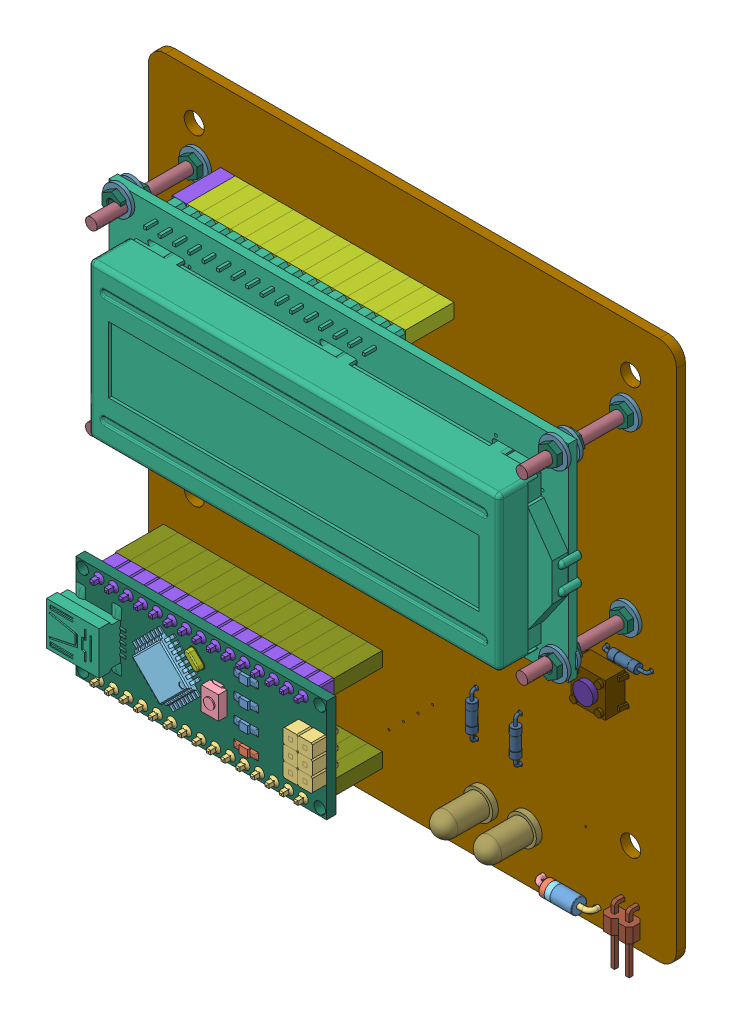
SolidWorks assembly PCB_V02, configuration Valor predeterminado. Lengths in mm.
Overall size (93.53 97.66 25.25).
163 component instances, 33 part files, 52 mates.
Components (placement in the parent):
- Gerador Senhas.stp-1: Gerador Senhas.stp [Valor predeterminado] at origin size (93.53 97.66 25.7)
  - PCB Component.stp-1: PCB Component.stp [Valor predeterminado] at origin size (93.53 97.66 25.7)
    - ARDUINO-NANO.stp-1: ARDUINO-NANO.stp [Valor predeterminado] at (39.37 21.59 1.57) x (0 -1 0) z (0 0 1) size (17.9 45.1 23.75)
      - PCB.stp-1: PCB.stp [Valor predeterminado] at (-1.2568 4.2028 12.5) x (0 -1 0) z (1 0 0) size (45.1 18 17.9)
        - TopFace.stp-1: TopFace.stp [Valor predeterminado] at origin size (45.1 11.25 12.1)
          - Leds.stp-1: Leds.stp [Valor predeterminado] at origin size (4.2 0.5 12.1)
            - Led.stp-1: Led.stp [Valor predeterminado] at (3.25 0 -13.6) size (4.2 0.5 1.3)
            - Led.stp-2: Led.stp [Valor predeterminado] at (3.25 0 -17.2) size (4.2 0.5 1.3)
            - Led.stp-3: Led.stp [Valor predeterminado] at (3.25 0 -20.8) size (4.2 0.5 1.3)
            - Led (1).stp-1: Led (1).stp [Valor predeterminado] at (3.25 0 -10) size (4.2 0.5 1.3)
          - PinEnd.stp-1: PinEnd.stp [Valor predeterminado] at (0 0 -2.54) size (5.08 11.25 7.62)
            - Pin.stp-1: Pin.stp [Valor predeterminado] at (25 1.6 57.68) x (1 0 0) z (0 0 -1) size (2.54 11.25 2.54)
            - Pin.stp-2: Pin.stp [Valor predeterminado] at (25 1.6 60.22) x (1 0 0) z (0 0 -1) size (2.54 11.25 2.54)
            - Pin.stp-3: Pin.stp [Valor predeterminado] at (25 1.6 62.76) x (1 0 0) z (0 0 -1) size (2.54 11.25 2.54)
            - Pin.stp-4: Pin.stp [Valor predeterminado] at (27.54 1.6 57.68) x (1 0 0) z (0 0 -1) size (2.54 11.25 2.54)
            - Pin.stp-5: Pin.stp [Valor predeterminado] at (27.54 1.6 60.22) x (1 0 0) z (0 0 -1) size (2.54 11.25 2.54)
            - Pin.stp-6: Pin.stp [Valor predeterminado] at (27.54 1.6 62.76) x (1 0 0) z (0 0 -1) size (2.54 11.25 2.54)
          - switch.stp-1: switch.stp [Valor predeterminado] at (1.3966 -1.5 22.3391) size (3 1.7 4.8)
          - chip1.stp-1: chip1.stp [Valor predeterminado] at origin size (11.76 1.3 11.76)
          - USB.stp-1: USB.stp [Valor predeterminado] at origin size (10.18 3.8 11.01)
          - Crystal.stp-1: Crystal.stp [Valor predeterminado] at origin size (2.71 1.1 2.71)
        - BottomFace.stp-1: BottomFace.stp [Valor predeterminado] at origin size (40.75 11.25 17.9)
          - PinRow2.stp-1: PinRow2.stp [Valor predeterminado] at (0 0 17.9) size (38.1 11.25 2.54)
            - Pin (1).stp-1: Pin (1).stp [Valor predeterminado] at (45.58 0 32.1) size (2.54 11.25 2.54)
            - Pin (1).stp-2: Pin (1).stp [Valor predeterminado] at (48.12 0 32.1) size (2.54 11.25 2.54)
            - Pin (1).stp-3: Pin (1).stp [Valor predeterminado] at (50.66 0 32.1) size (2.54 11.25 2.54)
            - Pin (1).stp-4: Pin (1).stp [Valor predeterminado] at (53.2 0 32.1) size (2.54 11.25 2.54)
            - Pin (1).stp-5: Pin (1).stp [Valor predeterminado] at (55.74 0 32.1) size (2.54 11.25 2.54)
            - Pin (1).stp-6: Pin (1).stp [Valor predeterminado] at (58.28 0 32.1) size (2.54 11.25 2.54)
            - Pin (1).stp-7: Pin (1).stp [Valor predeterminado] at (60.82 0 32.1) size (2.54 11.25 2.54)
            - Pin (1).stp-8: Pin (1).stp [Valor predeterminado] at (63.36 0 32.1) size (2.54 11.25 2.54)
            - Pin (1).stp-9: Pin (1).stp [Valor predeterminado] at (43.04 0 32.1) size (2.54 11.25 2.54)
            - Pin (1).stp-10: Pin (1).stp [Valor predeterminado] at (40.5 0 32.1) size (2.54 11.25 2.54)
            - Pin (1).stp-11: Pin (1).stp [Valor predeterminado] at (37.96 0 32.1) size (2.54 11.25 2.54)
            - Pin (1).stp-12: Pin (1).stp [Valor predeterminado] at (35.42 0 32.1) size (2.54 11.25 2.54)
            - Pin (1).stp-13: Pin (1).stp [Valor predeterminado] at (32.88 0 32.1) size (2.54 11.25 2.54)
            - Pin (1).stp-14: Pin (1).stp [Valor predeterminado] at (30.34 0 32.1) size (2.54 11.25 2.54)
            - Pin (1).stp-15: Pin (1).stp [Valor predeterminado] at (27.8 0 32.1) size (2.54 11.25 2.54)
          - PinRow1.stp-1: PinRow1.stp [Valor predeterminado] at origin size (38.1 11.25 2.54)
            - Pin.stp-1: Pin.stp [Valor predeterminado] at (45.58 0 -32.1) size (2.54 11.25 2.54)
            - Pin.stp-2: Pin.stp [Valor predeterminado] at (48.12 0 -32.1) size (2.54 11.25 2.54)
            - Pin.stp-3: Pin.stp [Valor predeterminado] at (50.66 0 -32.1) size (2.54 11.25 2.54)
            - Pin.stp-4: Pin.stp [Valor predeterminado] at (53.2 0 -32.1) size (2.54 11.25 2.54)
            - Pin.stp-5: Pin.stp [Valor predeterminado] at (55.74 0 -32.1) size (2.54 11.25 2.54)
            - Pin.stp-6: Pin.stp [Valor predeterminado] at (58.28 0 -32.1) size (2.54 11.25 2.54)
            - Pin.stp-7: Pin.stp [Valor predeterminado] at (60.82 0 -32.1) size (2.54 11.25 2.54)
            - Pin.stp-8: Pin.stp [Valor predeterminado] at (63.36 0 -32.1) size (2.54 11.25 2.54)
            - Pin.stp-9: Pin.stp [Valor predeterminado] at (43.04 0 -32.1) size (2.54 11.25 2.54)
            - Pin.stp-10: Pin.stp [Valor predeterminado] at (40.5 0 -32.1) size (2.54 11.25 2.54)
            - Pin.stp-11: Pin.stp [Valor predeterminado] at (37.96 0 -32.1) size (2.54 11.25 2.54)
            - Pin.stp-12: Pin.stp [Valor predeterminado] at (35.42 0 -32.1) size (2.54 11.25 2.54)
            - Pin.stp-13: Pin.stp [Valor predeterminado] at (32.88 0 -32.1) size (2.54 11.25 2.54)
            - Pin.stp-14: Pin.stp [Valor predeterminado] at (30.34 0 -32.1) size (2.54 11.25 2.54)
            - Pin.stp-15: Pin.stp [Valor predeterminado] at (27.8 0 -32.1) size (2.54 11.25 2.54)
          - Resistors.stp-1: Resistors.stp [Valor predeterminado] at origin size (32.5 1 11.3)
            - Res.stp-1: Res.stp [Valor predeterminado] at (12.2 1.6 29.15) x (0 0 -1) z (1 0 0) size (1.3 1 4)
            - Res.stp-2: Res.stp [Valor predeterminado] at (12.2 1.6 24.6) x (0 0 -1) z (1 0 0) size (1.3 1 4)
            - Res.stp-3: Res.stp [Valor predeterminado] at (-2.9 1.6 23.1) x (0 0 -1) z (1 0 0) size (1.3 1 4)
            - Res.stp-4: Res.stp [Valor predeterminado] at (-2.9 1.6 26.2) x (0 0 -1) z (1 0 0) size (1.3 1 4)
            - Res.stp-5: Res.stp [Valor predeterminado] at (-16.3 1.6 19.15) x (0 0 -1) z (1 0 0) size (1.3 1 4)
          - caps.stp-1: caps.stp [Valor predeterminado] at origin size (33.2 1.51 4.35)
            - cap.stp-1: cap.stp [Valor predeterminado] at (68.25 1.6 43.825) x (-1 0 0) z (0 0 -1) size (3.7 1.51 1.65)
            - cap.stp-2: cap.stp [Valor predeterminado] at (-14.35 1.6 -32.125) size (3.7 1.51 1.65)
          - respacks.stp-1: respacks.stp [Valor predeterminado] at origin size (3.22 0.9 8.4)
            - respack.stp-1: respack.stp [Valor predeterminado] at (-0.85 1.6 -21.8) size (3.22 0.9 3.4)
            - respack.stp-2: respack.stp [Valor predeterminado] at (-0.85 1.6 -26.8) size (3.22 0.9 3.4)
          - Chip.stp-1: Chip.stp [Valor predeterminado] at origin size (10 1.5 8.03)
          - diode.stp-1: diode.stp [Valor predeterminado] at (0.15 1.6 -28.35) size (1.6 1 4.3)
          - vreg.stp-1: vreg.stp [Valor predeterminado] at (-16.3 1.6 -15.5) size (8.5 1.6 6)
        - PCB-0.stp-1: PCB-0.stp [Valor predeterminado] at origin size (43.7 1.6 17.9)
      - Headers.stp-1: Headers.stp [Valor predeterminado] at (-1.2568 4.2028 12.5) x (0 -1 0) z (1 0 0) size (38.1 11.45 17.78)
        - Header Female 15 v1.stp-1: Header Female 15 v1.stp [Valor predeterminado] at (4.07 12.55 16.51) x (1 0 0) z (0 -1 0) size (38.1 2.54 11.45)
          - HF1.stp-1: HF1.stp [Valor predeterminado] at origin size (2.54 2.54 11.45)
          - HF1.stp-2: HF1.stp [Valor predeterminado] at (2.54 0 0) size (2.54 2.54 11.45)
          - HF1.stp-3: HF1.stp [Valor predeterminado] at (5.08 0 0) size (2.54 2.54 11.45)
          - HF1.stp-4: HF1.stp [Valor predeterminado] at (7.62 0 0) size (2.54 2.54 11.45)
          - HF1.stp-5: HF1.stp [Valor predeterminado] at (10.16 0 0) size (2.54 2.54 11.45)
          - HF1.stp-6: HF1.stp [Valor predeterminado] at (12.7 0 0) size (2.54 2.54 11.45)
          - HF1.stp-7: HF1.stp [Valor predeterminado] at (15.24 0 0) size (2.54 2.54 11.45)
          - HF1.stp-8: HF1.stp [Valor predeterminado] at (17.78 0 0) size (2.54 2.54 11.45)
          - HF1.stp-9: HF1.stp [Valor predeterminado] at (20.32 0 0) size (2.54 2.54 11.45)
          - HF1.stp-10: HF1.stp [Valor predeterminado] at (22.86 0 0) size (2.54 2.54 11.45)
          - HF1.stp-11: HF1.stp [Valor predeterminado] at (25.4 0 0) size (2.54 2.54 11.45)
          - HF1.stp-12: HF1.stp [Valor predeterminado] at (27.94 0 0) size (2.54 2.54 11.45)
          - HF1.stp-13: HF1.stp [Valor predeterminado] at (30.48 0 0) size (2.54 2.54 11.45)
          - HF1.stp-14: HF1.stp [Valor predeterminado] at (33.02 0 0) size (2.54 2.54 11.45)
          - HF1.stp-15: HF1.stp [Valor predeterminado] at (35.56 0 0) size (2.54 2.54 11.45)
        - Header Female 15 v1 (1).stp-1: Header Female 15 v1 (1).stp [Valor predeterminado] at (4.07 12.55 1.27) x (1 0 0) z (0 -1 0) size (38.1 2.54 11.45)
          - HF1.stp-1: HF1.stp [Valor predeterminado] at origin size (2.54 2.54 11.45)
          - HF1.stp-2: HF1.stp [Valor predeterminado] at (2.54 0 0) size (2.54 2.54 11.45)
          - HF1.stp-3: HF1.stp [Valor predeterminado] at (5.08 0 0) size (2.54 2.54 11.45)
          - HF1.stp-4: HF1.stp [Valor predeterminado] at (7.62 0 0) size (2.54 2.54 11.45)
          - HF1.stp-5: HF1.stp [Valor predeterminado] at (10.16 0 0) size (2.54 2.54 11.45)
          - HF1.stp-6: HF1.stp [Valor predeterminado] at (12.7 0 0) size (2.54 2.54 11.45)
          - HF1.stp-7: HF1.stp [Valor predeterminado] at (15.24 0 0) size (2.54 2.54 11.45)
          - HF1.stp-8: HF1.stp [Valor predeterminado] at (17.78 0 0) size (2.54 2.54 11.45)
          - HF1.stp-9: HF1.stp [Valor predeterminado] at (20.32 0 0) size (2.54 2.54 11.45)
          - HF1.stp-10: HF1.stp [Valor predeterminado] at (22.86 0 0) size (2.54 2.54 11.45)
          - HF1.stp-11: HF1.stp [Valor predeterminado] at (25.4 0 0) size (2.54 2.54 11.45)
          - HF1.stp-12: HF1.stp [Valor predeterminado] at (27.94 0 0) size (2.54 2.54 11.45)
          - HF1.stp-13: HF1.stp [Valor predeterminado] at (30.48 0 0) size (2.54 2.54 11.45)
          - HF1.stp-14: HF1.stp [Valor predeterminado] at (33.02 0 0) size (2.54 2.54 11.45)
          - HF1.stp-15: HF1.stp [Valor predeterminado] at (35.56 0 0) size (2.54 2.54 11.45)
    - PUSHBUTTON.stp-1: PUSHBUTTON.stp [Valor predeterminado] at (12 38.1 1.57) size (7.7 6 7.8)
      - B3F_1000_BUTTON.stp-1: B3F_1000_BUTTON.stp [Valor predeterminado] at (0 0 4.3) x (-1 0 0) z (0 1 0) size (3.5 1 3.5)
      - B3F_1000_BASE.stp-1: B3F_1000_BASE.stp [Valor predeterminado] x (1 0 0) z (0 -1 0) size (7.7 7.4 6)
    - PUSHBUTTON.stp-2: PUSHBUTTON.stp [Valor predeterminado] at (34.667 38.1 1.57) size (7.7 6 7.8)
      - B3F_1000_BUTTON.stp-1: B3F_1000_BUTTON.stp [Valor predeterminado] at (0 0 4.3) x (-1 0 0) z (0 1 0) size (3.5 1 3.5)
      - B3F_1000_BASE.stp-1: B3F_1000_BASE.stp [Valor predeterminado] x (1 0 0) z (0 -1 0) size (7.7 7.4 6)
    - PUSHBUTTON.stp-3: PUSHBUTTON.stp [Valor predeterminado] at (57.333 38.1 1.57) size (7.7 6 7.8)
      - B3F_1000_BUTTON.stp-1: B3F_1000_BUTTON.stp [Valor predeterminado] at (0 0 4.3) x (-1 0 0) z (0 1 0) size (3.5 1 3.5)
      - B3F_1000_BASE.stp-1: B3F_1000_BASE.stp [Valor predeterminado] x (1 0 0) z (0 -1 0) size (7.7 7.4 6)
    - PUSHBUTTON.stp-4: PUSHBUTTON.stp [Valor predeterminado] at (80 38.1 1.57) size (7.7 6 7.8)
      - B3F_1000_BUTTON.stp-1: B3F_1000_BUTTON.stp [Valor predeterminado] at (0 0 4.3) x (-1 0 0) z (0 1 0) size (3.5 1 3.5)
      - B3F_1000_BASE.stp-1: B3F_1000_BASE.stp [Valor predeterminado] x (1 0 0) z (0 -1 0) size (7.7 7.4 6)
    - 1N4004.stp-1: 1N4004.stp [Valor predeterminado] at (73.66 2.54 1.57) size (10.38 2.7 5.35)
      - User Library-DO-41_375mil_Fillet001.stp-1: User Library-DO-41_375mil_Fillet001.stp [Valor predeterminado] at (4.7457 0.3612 0) x (-1 0 0) z (0 0 1) size (3.72 2.7 2.7)
      - User Library-DO-41_375mil_Fillet.stp-1: User Library-DO-41_375mil_Fillet.stp [Valor predeterminado] at (4.7457 0.3612 0) x (-1 0 0) z (0 0 1) size (1 2.7 2.7)
      - User Library-DO-41_375mil_DO_41_375mil001.stp-1: User Library-DO-41_375mil_DO_41_375mil001.stp [Valor predeterminado] at (4.7457 0.3612 0) x (-1 0 0) z (0 0 1) size (2.55 0.86 4.43)
      - User Library-DO-41_375mil_DO_41_375mil.stp-1: User Library-DO-41_375mil_DO_41_375mil.stp [Valor predeterminado] at (4.7457 0.3612 0) x (-1 0 0) z (0 0 1) size (2.55 0.86 4.43)
      - User Library-DO-41_375mil_DO_41_375mil003.stp-1: User Library-DO-41_375mil_DO_41_375mil003.stp [Valor predeterminado] at (4.7457 0.3612 0) x (-1 0 0) z (0 0 1) size (1 2.7 2.7)
    - LCD-16X2-V2.stp-1: LCD-16X2-V2.stp [Valor predeterminado] at (46 64.77 1.57) size (80.7 36 23.25)
      - DISPLAY-LCD.stp-1: DISPLAY-LCD.stp [Valor predeterminado] at (-0.3985 0.0488 8.5541) size (80.7 36 16.8)
      - Header Female 15 v1 (2).stp-1: Header Female 15 v1 (2).stp [Valor predeterminado] at (-29.5885 15.5718 0.0005) size (38.1 2.54 11.45)
      - Header Female 15 v1 - Copia.stp-1: Header Female 15 v1 - Copia.stp [Valor predeterminado] at (-32.1285 15.5718 0.0005) size (2.54 2.54 11.45)
    - Board.stp-1: Board.stp [Valor predeterminado] at origin size (92 94 1.57)
    - 10k.stp-1: 10k.stp [Valor predeterminado] at (57.15 21.59 1.57) x (0 1 0) z (0 0 1) size (8.2 1.6 3.52)
    - 10k.stp-2: 10k.stp [Valor predeterminado] at (64.77 21.59 1.57) x (0 1 0) z (0 0 1) size (8.2 1.6 3.52)
    - 10k.stp-3: 10k.stp [Valor predeterminado] at (15.24 43.18 1.57) size (8.2 1.6 3.52)
    - 10k.stp-4: 10k.stp [Valor predeterminado] at (38.1 43.18 1.57) size (8.2 1.6 3.52)
    - 10k.stp-5: 10k.stp [Valor predeterminado] at (60.96 43.18 1.57) size (8.2 1.6 3.52)
    - 10k.stp-6: 10k.stp [Valor predeterminado] at (83.82 43.18 1.57) size (8.2 1.6 3.52)
    - 1X02_90.stp-1: 1X02_90.stp [Valor predeterminado] at (83.82 2.54 1.57) x (-1 0 0) z (0 0 1) size (5.08 10.36 5.54)
    - LED5MM.stp-1: LED5MM.stp [Valor predeterminado] at (58.42 8.89 1.57) size (5.1 5.1 13.6)
    - LED5MM.stp-2: LED5MM.stp [Valor predeterminado] at (66.04 8.89 1.57) size (5.1 5.1 13.6)
- pan head cross recess screw_iso-1: pan head cross recess screw_iso [ISO 7045 - M2 x 20 - Z - 20N] at (83.5 80.27 -1.6) x (0 0 1) z (-1 0 0) size (21.57 4 4)
- pan head cross recess screw_iso-2: pan head cross recess screw_iso [ISO 7045 - M2 x 20 - Z - 20N] at (83.5 49.27 -1.6) x (0 0 1) z (-1 0 0) size (21.57 4 4)
- pan head cross recess screw_iso-3: pan head cross recess screw_iso [ISO 7045 - M2 x 20 - Z - 20N] at (8.5 49.27 -1.6) x (0 0 1) z (-1 0 0) size (21.57 4 4)
- pan head cross recess screw_iso-4: pan head cross recess screw_iso [ISO 7045 - M2 x 20 - Z - 20N] at (8.5 80.27 -1.6) x (0 0 1) z (-1 0 0) size (21.57 4 4)
- plain washer 10673 type snl_iso-1: plain washer 10673 type snl_iso [ISO 10673-2.25-S] at (83.5 80.27 1.57) x (0 0 1) z (-1 0 0) size (0.6 5 5)
- plain washer 10673 type snl_iso-2: plain washer 10673 type snl_iso [ISO 10673-2.25-S] at (83.6015 80.6118 14.0205) x (0 0 1) z (-1 0 0) size (0.6 5 5)
- plain washer 10673 type snl_iso-3: plain washer 10673 type snl_iso [ISO 10673-2.25-S] at (83.6015 80.6118 12.5205) x (0 0 -1) z (1 0 0) size (0.6 5 5)
- plain washer 10673 type snl_iso-4: plain washer 10673 type snl_iso [ISO 10673-2.25-S] at (83.5 49.27 12.2061) x (0 0 1) z (-1 0 0) size (0.6 5 5)
- plain washer 10673 type snl_iso-5: plain washer 10673 type snl_iso [ISO 10673-2.25-S] at (83.6015 48.6118 14.0205) x (0 0 1) z (-1 0 0) size (0.6 5 5)
- plain washer 10673 type snl_iso-6: plain washer 10673 type snl_iso [ISO 10673-2.25-S] at (83.5 49.27 1.57) x (0 0 1) z (-1 0 0) size (0.6 5 5)
- plain washer 10673 type snl_iso-7: plain washer 10673 type snl_iso [ISO 10673-2.25-S] at (8.5 49.27 1.763) x (0 0 1) z (-1 0 0) size (0.6 5 5)
- plain washer 10673 type snl_iso-8: plain washer 10673 type snl_iso [ISO 10673-2.25-S] at (7.6015 48.6118 14.0205) x (0 0 1) z (-1 0 0) size (0.6 5 5)
- plain washer 10673 type snl_iso-9: plain washer 10673 type snl_iso [ISO 10673-2.25-S] at (7.6015 80.6118 14.0205) x (0 0 1) z (-1 0 0) size (0.6 5 5)
- plain washer 10673 type snl_iso-10: plain washer 10673 type snl_iso [ISO 10673-2.25-S] at (8.5 80.27 1.57) x (0 0 1) z (-1 0 0) size (0.6 5 5)
- plain washer 10673 type snl_iso-12: plain washer 10673 type snl_iso [ISO 10673-2.25-S] at (7.6015 48.6118 12.5205) x (0 0 -1) z (1 0 0) size (0.6 5 5)
- plain washer 10673 type snl_iso-13: plain washer 10673 type snl_iso [ISO 10673-2.25-S] at (7.6015 80.6118 12.5205) x (0 0 -1) z (1 0 0) size (0.6 5 5)
- hex thin nut gradeb_iso-2: hex thin nut gradeb_iso [ISO - 4036 - M1.6 - N] at (83.6015 80.6118 15.6205) size (3.2 3.7 1)
- hex thin nut gradeb_iso-3: hex thin nut gradeb_iso [ISO - 4036 - M1.6 - N] at (83.5 80.27 3.17) size (3.2 3.7 1)
- hex thin nut gradeb_iso-4: hex thin nut gradeb_iso [ISO - 4036 - M1.6 - N] at (83.6015 80.6118 10.9205) x (0.923728 0.383049 0) z (0 0 -1) size (3.2 3.7 1)
- hex thin nut gradeb_iso-5: hex thin nut gradeb_iso [ISO - 4036 - M1.6 - N] at (83.5 49.27 11.2061) x (0.923728 0.383049 0) z (0 0 -1) size (3.2 3.7 1)
- hex thin nut gradeb_iso-6: hex thin nut gradeb_iso [ISO - 4036 - M1.6 - N] at (83.5 49.27 3.17) size (3.2 3.7 1)
- hex thin nut gradeb_iso-7: hex thin nut gradeb_iso [ISO - 4036 - M1.6 - N] at (83.6015 48.6118 15.6205) size (3.2 3.7 1)
- hex thin nut gradeb_iso-8: hex thin nut gradeb_iso [ISO - 4036 - M1.6 - N] at (7.6015 80.6118 15.6205) size (3.2 3.7 1)
- hex thin nut gradeb_iso-9: hex thin nut gradeb_iso [ISO - 4036 - M1.6 - N] at (7.6015 48.6118 15.6205) size (3.2 3.7 1)
- hex thin nut gradeb_iso-10: hex thin nut gradeb_iso [ISO - 4036 - M1.6 - N] at (7.6015 48.6118 10.9205) x (0.923728 0.383049 0) z (0 0 -1) size (3.2 3.7 1)
- hex thin nut gradeb_iso-11: hex thin nut gradeb_iso [ISO - 4036 - M1.6 - N] at (8.5 80.27 10.9205) x (-0.825808 -0.563951 0) z (0 0 -1) size (3.2 3.7 1)
- hex thin nut gradeb_iso-12: hex thin nut gradeb_iso [ISO - 4036 - M1.6 - N] at (8.5 80.27 3.17) size (3.2 3.7 1)
- hex thin nut gradeb_iso-13: hex thin nut gradeb_iso [ISO - 4036 - M1.6 - N] at (8.5 49.27 3.363) size (3.2 3.7 1)
Mates (geometry in assembly coordinates):
- Concêntrico1: concentric anti-aligned: cylinder of Gerador Senhas.stp-1/PCB Component.stp-1/Board.stp-1 through (83.5 80.27 0) axis (0 0 1) radius 1.25; cylinder of pan head cross recess screw_iso-1 through (83.5 80.27 -27) axis (0 0 -1) radius 2
- Coincidente1: coincident anti-aligned: plane of Gerador Senhas.stp-1/PCB Component.stp-1/Board.stp-1 through (46 47 0) normal (0 0 -1); plane of pan head cross recess screw_iso-1 through (83.5 81.27 0) normal (0 0 1)
- Concêntrico2: concentric anti-aligned: cylinder of Gerador Senhas.stp-1/PCB Component.stp-1/Board.stp-1 through (83.5 49.27 0) axis (0 0 1) radius 1.25; cylinder of pan head cross recess screw_iso-2 through (83.5 49.27 -27) axis (0 0 -1) radius 2
- Coincidente2: coincident anti-aligned: plane of Gerador Senhas.stp-1/PCB Component.stp-1/Board.stp-1 through (46 47 0) normal (0 0 -1); plane of pan head cross recess screw_iso-2 through (83.5 50.27 0) normal (0 0 1)
- Concêntrico3: concentric anti-aligned: cylinder of Gerador Senhas.stp-1/PCB Component.stp-1/Board.stp-1 through (8.5 49.27 0) axis (0 0 1) radius 1.25; cylinder of pan head cross recess screw_iso-3 through (8.5 49.27 -27) axis (0 0 -1) radius 2
- Coincidente3: coincident anti-aligned: plane of Gerador Senhas.stp-1/PCB Component.stp-1/Board.stp-1 through (46 47 0) normal (0 0 -1); plane of pan head cross recess screw_iso-3 through (8.5 50.27 0) normal (0 0 1)
- Concêntrico4: concentric anti-aligned: cylinder of Gerador Senhas.stp-1/PCB Component.stp-1/Board.stp-1 through (8.5 80.27 0) axis (0 0 1) radius 1.25; cylinder of pan head cross recess screw_iso-4 through (8.5 80.27 -27) axis (0 0 -1) radius 2
- Coincidente4: coincident anti-aligned: plane of Gerador Senhas.stp-1/PCB Component.stp-1/Board.stp-1 through (46 47 0) normal (0 0 -1); plane of pan head cross recess screw_iso-4 through (8.5 81.27 0) normal (0 0 1)
- Concêntrico6: concentric anti-aligned: cylinder of Gerador Senhas.stp-1/PCB Component.stp-1/Board.stp-1 through (83.5 80.27 0) axis (0 0 1) radius 1.25; cylinder of plain washer 10673 type snl_iso-1 through (83.5 80.27 2.17) axis (0 0 -1) radius 1.125
- Coincidente5: coincident anti-aligned: plane of Gerador Senhas.stp-1/PCB Component.stp-1/Board.stp-1 through (46 47 1.57) normal (0 0 1); plane of plain washer 10673 type snl_iso-1 through (83.5 80.27 1.57) normal (0 0 -1)
- Concêntrico7: concentric aligned: cylinder of Gerador Senhas.stp-1/PCB Component.stp-1/LCD-16X2-V2.stp-1/DISPLAY-LCD.stp-1 through (83.6015 80.6118 12.5205) axis (0 0 -1) radius 1.5; cylinder of plain washer 10673 type snl_iso-2 through (83.6015 80.6118 14.6205) axis (0 0 -1) radius 1.125
- Coincidente6: coincident anti-aligned: plane of Gerador Senhas.stp-1/PCB Component.stp-1/LCD-16X2-V2.stp-1/DISPLAY-LCD.stp-1 through (45.6015 64.6118 14.0205) normal (0 0 1); plane of plain washer 10673 type snl_iso-2 through (83.6015 80.6118 14.0205) normal (0 0 -1)
- Concêntrico8: concentric anti-aligned: cylinder of Gerador Senhas.stp-1/PCB Component.stp-1/LCD-16X2-V2.stp-1/DISPLAY-LCD.stp-1 through (83.6015 80.6118 12.5205) axis (0 0 -1) radius 1.5; cylinder of plain washer 10673 type snl_iso-3 through (83.6015 80.6118 11.9205) axis (0 0 1) radius 1.125
- Coincidente7: coincident anti-aligned: plane of Gerador Senhas.stp-1/PCB Component.stp-1/LCD-16X2-V2.stp-1/DISPLAY-LCD.stp-1 through (45.6015 64.6118 12.5205) normal (0 0 -1); plane of plain washer 10673 type snl_iso-3 through (83.6015 80.6118 12.5205) normal (0 0 1)
- Concêntrico9: concentric aligned: cylinder of pan head cross recess screw_iso-2 through (83.5 49.27 -27) axis (0 0 -1) radius 1; cylinder of plain washer 10673 type snl_iso-4 through (83.5 49.27 12.8061) axis (0 0 -1) radius 1.125
- Concêntrico10: concentric aligned: cylinder of Gerador Senhas.stp-1/PCB Component.stp-1/LCD-16X2-V2.stp-1/DISPLAY-LCD.stp-1 through (83.6015 48.6118 12.5205) axis (0 0 -1) radius 1.5; cylinder of plain washer 10673 type snl_iso-5 through (83.6015 48.6118 14.6205) axis (0 0 -1) radius 1.125
- Coincidente8: coincident anti-aligned: plane of Gerador Senhas.stp-1/PCB Component.stp-1/LCD-16X2-V2.stp-1/DISPLAY-LCD.stp-1 through (45.6015 64.6118 14.0205) normal (0 0 1); plane of plain washer 10673 type snl_iso-5 through (83.6015 48.6118 14.0205) normal (0 0 -1)
- Concêntrico11: concentric anti-aligned: cylinder of Gerador Senhas.stp-1/PCB Component.stp-1/Board.stp-1 through (83.5 49.27 0) axis (0 0 1) radius 1.25; cylinder of plain washer 10673 type snl_iso-6 through (83.5 49.27 2.17) axis (0 0 -1) radius 1.125
- Coincidente9: coincident anti-aligned: plane of Gerador Senhas.stp-1/PCB Component.stp-1/Board.stp-1 through (46 47 1.57) normal (0 0 1); plane of plain washer 10673 type snl_iso-6 through (83.5 49.27 1.57) normal (0 0 -1)
- Concêntrico12: concentric aligned: cylinder of pan head cross recess screw_iso-3 through (8.5 49.27 -27) axis (0 0 -1) radius 1; cylinder of plain washer 10673 type snl_iso-7 through (8.5 49.27 2.363) axis (0 0 -1) radius 1.125
- Concêntrico13: concentric aligned: cylinder of Gerador Senhas.stp-1/PCB Component.stp-1/LCD-16X2-V2.stp-1/DISPLAY-LCD.stp-1 through (7.6015 48.6118 12.5205) axis (0 0 -1) radius 1.5; cylinder of plain washer 10673 type snl_iso-8 through (7.6015 48.6118 14.6205) axis (0 0 -1) radius 1.125
- Coincidente10: coincident anti-aligned: plane of Gerador Senhas.stp-1/PCB Component.stp-1/LCD-16X2-V2.stp-1/DISPLAY-LCD.stp-1 through (45.6015 64.6118 14.0205) normal (0 0 1); plane of plain washer 10673 type snl_iso-8 through (7.6015 48.6118 14.0205) normal (0 0 -1)
- Concêntrico14: concentric aligned: cylinder of Gerador Senhas.stp-1/PCB Component.stp-1/LCD-16X2-V2.stp-1/DISPLAY-LCD.stp-1 through (7.6015 80.6118 12.5205) axis (0 0 -1) radius 1.5; cylinder of plain washer 10673 type snl_iso-9 through (7.6015 80.6118 14.6205) axis (0 0 -1) radius 1.125
- Coincidente11: coincident anti-aligned: plane of Gerador Senhas.stp-1/PCB Component.stp-1/LCD-16X2-V2.stp-1/DISPLAY-LCD.stp-1 through (45.6015 64.6118 14.0205) normal (0 0 1); plane of plain washer 10673 type snl_iso-9 through (7.6015 80.6118 14.0205) normal (0 0 -1)
- Concêntrico15: concentric anti-aligned: cylinder of Gerador Senhas.stp-1/PCB Component.stp-1/Board.stp-1 through (8.5 80.27 0) axis (0 0 1) radius 1.25; cylinder of plain washer 10673 type snl_iso-10 through (8.5 80.27 2.17) axis (0 0 -1) radius 1.125
- Coincidente12: coincident anti-aligned: plane of Gerador Senhas.stp-1/PCB Component.stp-1/Board.stp-1 through (46 47 1.57) normal (0 0 1); plane of plain washer 10673 type snl_iso-10 through (8.5 80.27 1.57) normal (0 0 -1)
- Concêntrico17: concentric anti-aligned: cylinder of Gerador Senhas.stp-1/PCB Component.stp-1/LCD-16X2-V2.stp-1/DISPLAY-LCD.stp-1 through (7.6015 48.6118 12.5205) axis (0 0 -1) radius 1.5; cylinder of plain washer 10673 type snl_iso-12 through (7.6015 48.6118 11.9205) axis (0 0 1) radius 1.125
- Coincidente13: coincident anti-aligned: plane of Gerador Senhas.stp-1/PCB Component.stp-1/LCD-16X2-V2.stp-1/DISPLAY-LCD.stp-1 through (45.6015 64.6118 12.5205) normal (0 0 -1); plane of plain washer 10673 type snl_iso-12 through (7.6015 48.6118 12.5205) normal (0 0 1)
- Concêntrico181: concentric anti-aligned: cylinder of Gerador Senhas.stp-1/PCB Component.stp-1/LCD-16X2-V2.stp-1/DISPLAY-LCD.stp-1 through (7.6015 80.6118 12.5205) axis (0 0 -1) radius 1.5; cylinder of plain washer 10673 type snl_iso-13 through (7.6015 80.6118 11.9205) axis (0 0 1) radius 1.125
- Coincidente141: coincident anti-aligned: plane of Gerador Senhas.stp-1/PCB Component.stp-1/LCD-16X2-V2.stp-1/DISPLAY-LCD.stp-1 through (45.6015 64.6118 12.5205) normal (0 0 -1); plane of plain washer 10673 type snl_iso-13 through (7.6015 80.6118 12.5205) normal (0 0 1)
- Concêntrico20: concentric anti-aligned: cylinder of plain washer 10673 type snl_iso-2 through (83.6015 80.6118 14.6205) axis (0 0 -1) radius 1.125; cylinder of hex thin nut gradeb_iso-2 through (83.6015 80.6118 -9.417) axis (0 0 1) radius 0.8
- Coincidente16: coincident anti-aligned: plane of plain washer 10673 type snl_iso-2 through (83.6015 80.6118 14.6205) normal (0 0 1); plane of hex thin nut gradeb_iso-2 through (83.6015 82.4594 14.6205) normal (0 0 -1)
- Concêntrico21: concentric anti-aligned: cylinder of plain washer 10673 type snl_iso-1 through (83.5 80.27 2.17) axis (0 0 -1) radius 1.125; cylinder of hex thin nut gradeb_iso-3 through (83.5 80.27 -21.8675) axis (0 0 1) radius 0.8
- Coincidente17: coincident anti-aligned: plane of plain washer 10673 type snl_iso-1 through (83.5 80.27 2.17) normal (0 0 1); plane of hex thin nut gradeb_iso-3 through (83.5 82.1175 2.17) normal (0 0 -1)
- Concêntrico22: concentric anti-aligned: cylinder of plain washer 10673 type snl_iso-3 through (83.6015 80.6118 11.9205) axis (0 0 1) radius 1.125; cylinder of hex thin nut gradeb_iso-4 through (83.6015 80.6118 35.958) axis (0 0 -1) radius 0.8
- Coincidente18: coincident anti-aligned: plane of plain washer 10673 type snl_iso-3 through (83.6015 80.6118 11.9205) normal (0 0 -1); plane of hex thin nut gradeb_iso-4 through (84.3092 78.9052 11.9205) normal (0 0 1)
- Concêntrico23: concentric aligned: cylinder of plain washer 10673 type snl_iso-4 through (83.5 49.27 12.8061) axis (0 0 -1) radius 1.125; cylinder of hex thin nut gradeb_iso-5 through (83.5 49.27 36.2437) axis (0 0 -1) radius 0.8
- Coincidente19: coincident anti-aligned: plane of plain washer 10673 type snl_iso-4 through (83.5 49.27 12.2061) normal (0 0 -1); plane of hex thin nut gradeb_iso-5 through (84.2077 47.5634 12.2061) normal (0 0 1)
- Concêntrico24: concentric anti-aligned: cylinder of plain washer 10673 type snl_iso-6 through (83.5 49.27 2.17) axis (0 0 -1) radius 1.125; cylinder of hex thin nut gradeb_iso-6 through (83.5 49.27 -21.8675) axis (0 0 1) radius 0.8
- Coincidente20: coincident anti-aligned: plane of plain washer 10673 type snl_iso-6 through (83.5 49.27 2.17) normal (0 0 1); plane of hex thin nut gradeb_iso-6 through (83.5 51.1175 2.17) normal (0 0 -1)
- Concêntrico25: concentric anti-aligned: cylinder of plain washer 10673 type snl_iso-5 through (83.6015 48.6118 14.6205) axis (0 0 -1) radius 1.125; cylinder of hex thin nut gradeb_iso-7 through (83.6015 48.6118 -9.417) axis (0 0 1) radius 0.8
- Coincidente21: coincident anti-aligned: plane of plain washer 10673 type snl_iso-5 through (83.6015 48.6118 14.6205) normal (0 0 1); plane of hex thin nut gradeb_iso-7 through (83.6015 50.4594 14.6205) normal (0 0 -1)
- Concêntrico26: concentric anti-aligned: cylinder of plain washer 10673 type snl_iso-9 through (7.6015 80.6118 14.6205) axis (0 0 -1) radius 1.125; cylinder of hex thin nut gradeb_iso-8 through (7.6015 80.6118 -9.417) axis (0 0 1) radius 0.8
- Coincidente22: coincident anti-aligned: plane of plain washer 10673 type snl_iso-9 through (7.6015 80.6118 14.6205) normal (0 0 1); plane of hex thin nut gradeb_iso-8 through (7.6015 82.4594 14.6205) normal (0 0 -1)
- Concêntrico28: concentric anti-aligned: cylinder of plain washer 10673 type snl_iso-12 through (7.6015 48.6118 11.9205) axis (0 0 1) radius 1.125; cylinder of hex thin nut gradeb_iso-10 through (7.6015 48.6118 35.958) axis (0 0 -1) radius 0.8
- Coincidente24: coincident anti-aligned: plane of plain washer 10673 type snl_iso-12 through (7.6015 48.6118 11.9205) normal (0 0 -1); plane of hex thin nut gradeb_iso-10 through (8.3092 46.9052 11.9205) normal (0 0 1)
- Concêntrico29: concentric aligned: cylinder of pan head cross recess screw_iso-4 through (8.5 80.27 -27) axis (0 0 -1) radius 1; cylinder of hex thin nut gradeb_iso-11 through (8.5 80.27 35.958) axis (0 0 -1) radius 0.8
- Concêntrico30: concentric anti-aligned: cylinder of plain washer 10673 type snl_iso-10 through (8.5 80.27 2.17) axis (0 0 -1) radius 1.125; cylinder of hex thin nut gradeb_iso-12 through (8.5 80.27 -21.8675) axis (0 0 1) radius 0.8
- Coincidente25: coincident anti-aligned: plane of plain washer 10673 type snl_iso-10 through (8.5 80.27 2.17) normal (0 0 1); plane of hex thin nut gradeb_iso-12 through (8.5 82.1175 2.17) normal (0 0 -1)
- Concêntrico31: concentric anti-aligned: cylinder of plain washer 10673 type snl_iso-7 through (8.5 49.27 2.363) axis (0 0 -1) radius 1.125; cylinder of hex thin nut gradeb_iso-13 through (8.5 49.27 -21.6745) axis (0 0 1) radius 0.8
- Coincidente26: coincident anti-aligned: plane of plain washer 10673 type snl_iso-7 through (8.5 49.27 2.363) normal (0 0 1); plane of hex thin nut gradeb_iso-13 through (8.5 51.1175 2.363) normal (0 0 -1)
- Coincidente27: coincident anti-aligned: circle of plain washer 10673 type snl_iso-13; plane of hex thin nut gradeb_iso-11 through (7.4581 81.7957 11.9205) normal (0 0 1)
